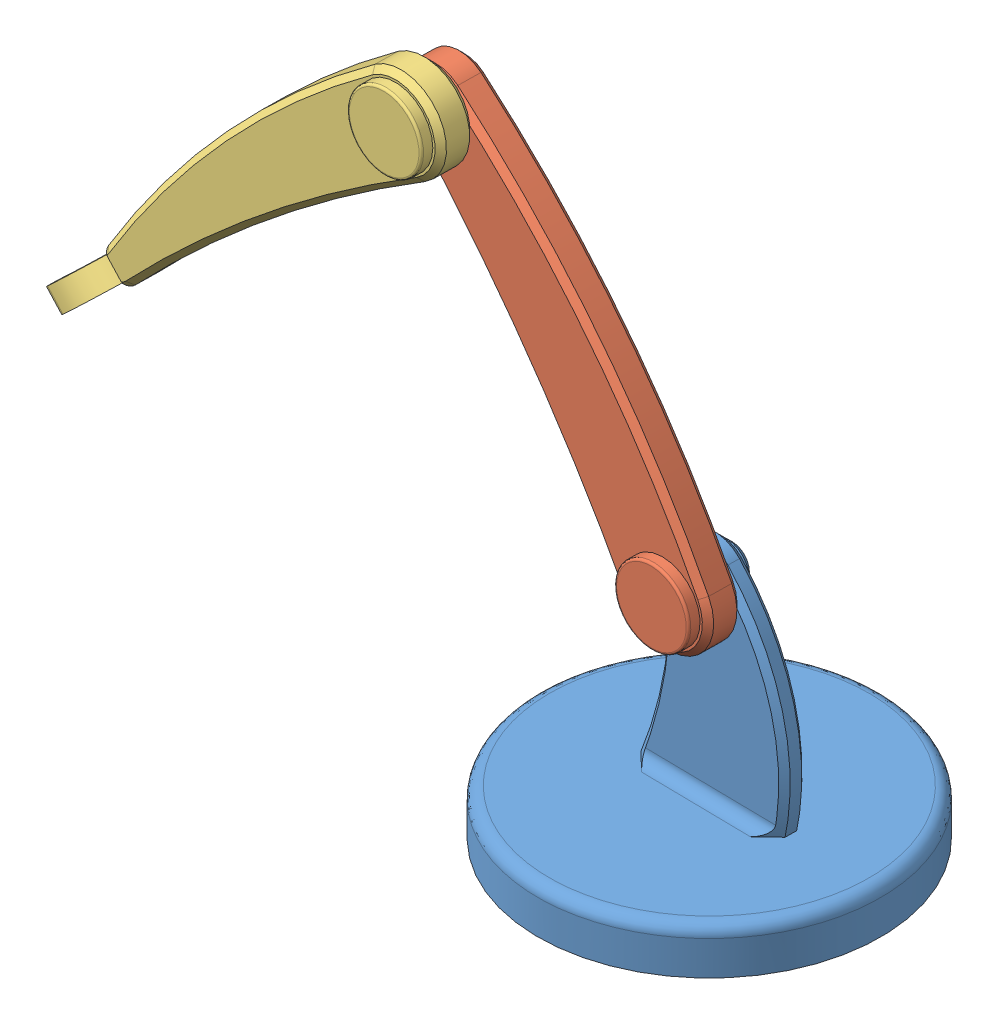
SolidWorks assembly Assem1, configuration Default. Lengths in mm.
Overall size (338.44 265.61 152.25).
3 component instances, 3 part files, 6 mates.
Components (placement in the parent):
- Part1-1: Part1 [Default] at (-114.6799 0 63.3042) x (-0.999886 0 -0.015129) z (0.015129 0 -0.999886) size (150 115 150)
- Part2-1: Part2 [Default] at (-166.5507 167.4788 75.0207) x (-0.60802 0.793868 -0.0092) z (-0.015129 0 0.999886) size (205 46.12 30)
- Part3-1: Part3 [Default] at (-280.3601 176.7131 88.3004) x (-0.728243 -0.68523 -0.011019) z (-0.015129 0 0.999886) size (215.42 43.27 36.9)
Mates (geometry in assembly coordinates):
- Coincident1: coincident aligned: plane of Part1-1 through (-114.6799 0 63.3042) normal (0 1 0)
- Coincident3: coincident anti-aligned: plane of Part1-1 through (-309.3517 87.8065 65.3591) normal (-0.015129 0 0.999886); plane of Part2-1 through (-166.4373 167.4788 67.5216) normal (0.015129 0 -0.999886)
- Concentric1: concentric aligned: cylinder of Part1-1 through (-114.6043 100 58.3047) axis (-0.015129 0 0.999886) radius 5; cylinder of Part2-1 through (-114.6043 100 58.3047) axis (-0.015129 0 0.999886) radius 5
- Coincident4: coincident anti-aligned: plane of Part2-1 through (-166.6642 167.4788 82.5199) normal (-0.015129 0 0.999886); plane of Part3-1 through (-280.2466 176.7131 80.8012) normal (0.015129 0 -0.999886)
- Concentric2: concentric aligned: cylinder of Part2-1 through (-218.1946 234.9576 71.739) axis (-0.015129 0 0.999886) radius 5; cylinder of Part3-1 through (-218.1946 234.9576 71.739) axis (-0.015129 0 0.999886) radius 5
- Perpendicular1: perpendicular: cylinder of Part1-1 through (-114.6799 20 63.3042) axis (0 -1 0) radius 75; cylinder of Part2-1 through (-703.9068 -219.3569 74.3908) axis (0.015129 0 -0.999886) radius 650
